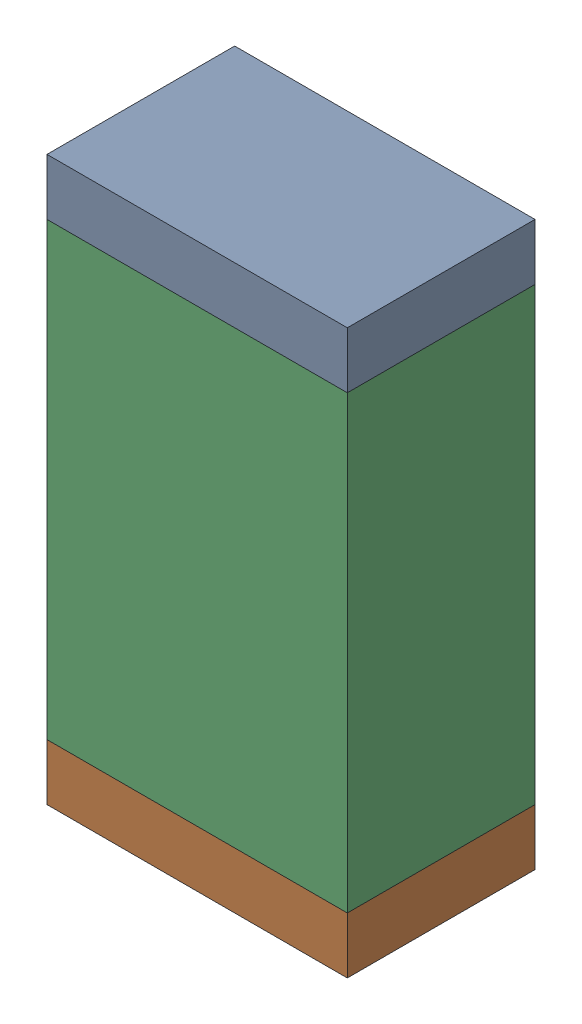
SolidWorks assembly R44, configuration Default. Lengths in mm.
Overall size (0.8 1.5 0.5).
6 component instances, 2 part files, 0 mates.
Components (placement in the parent):
- 810156592-1: 810156592 [Default] at (124.6 55.975 0) size (0.8 0.15 0.5)
  - Extruded_7-1: Extruded_7 [Default] at origin size (0.8 0.15 0.5)
- 810156592-2: 810156592 [Default] at (124.6 54.625 0) size (0.8 0.15 0.5)
  - Extruded_7-1: Extruded_7 [Default] at origin size (0.8 0.15 0.5)
- 810156976-1: 810156976 [Default] at (124.6 55.3 0) size (0.8 1.2 0.5)
  - Extruded_6-1: Extruded_6 [Default] at origin size (0.8 1.2 0.5)
